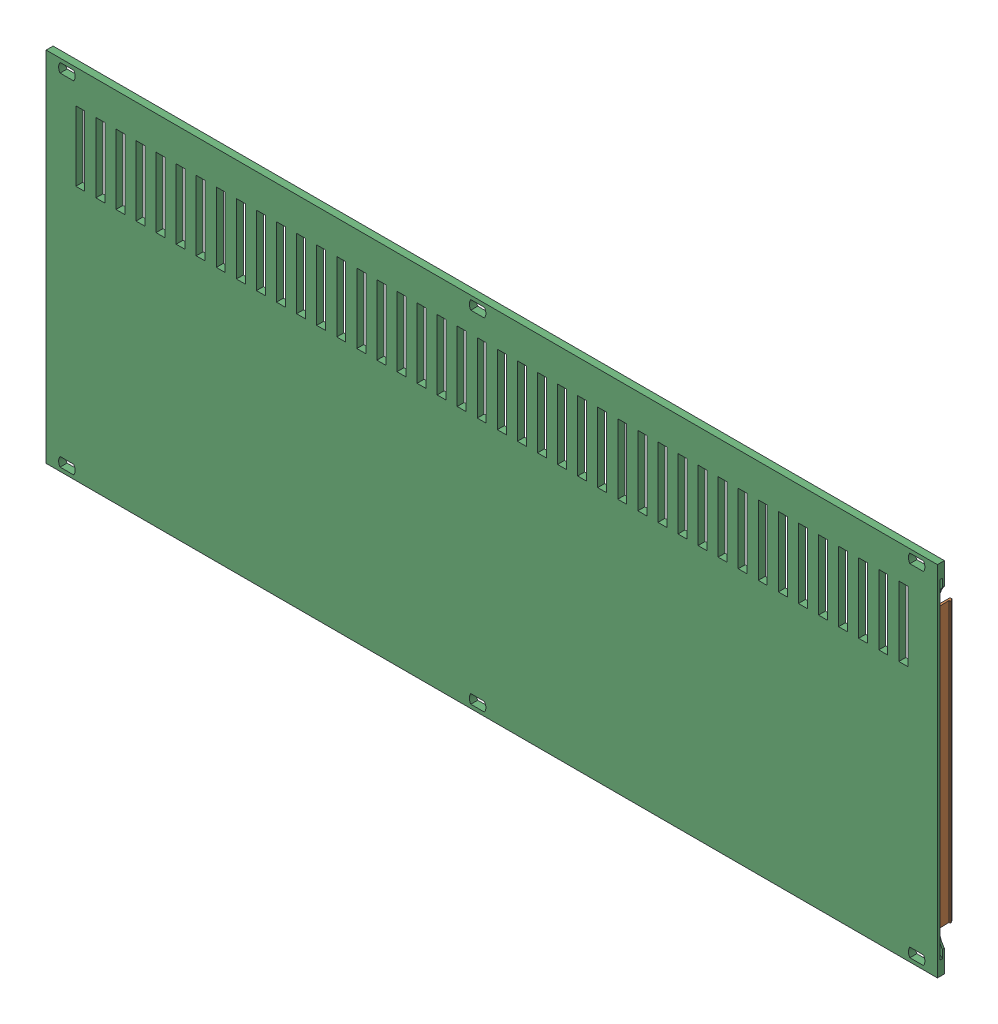
SolidWorks assembly RUECKWAND 3HE 63TE, configuration По умолчанию. Lengths in mm.
Overall size (319.7 128.4 6.2).
3 component instances, 3 part files, 0 mates.
Components (placement in the parent):
- 87654102-1: 87654102 [По умолчанию] at (-185.3361 158.8483 -131.2912) x (-1 0 0) z (0 -1 0) size (3.6 5.3 100)
- 87654117-1: 87654117 [По умолчанию] at (74.0139 158.8483 -131.2912) x (-1 0 0) z (0 -1 0) size (3.14 5.3 100)
- RUECKWAND 3HE 63TE-1: RUECKWAND 3HE 63TE [По умолчанию] at (-14.2678 126.7846 -55.3601) size (319.7 128.4 2.5)
